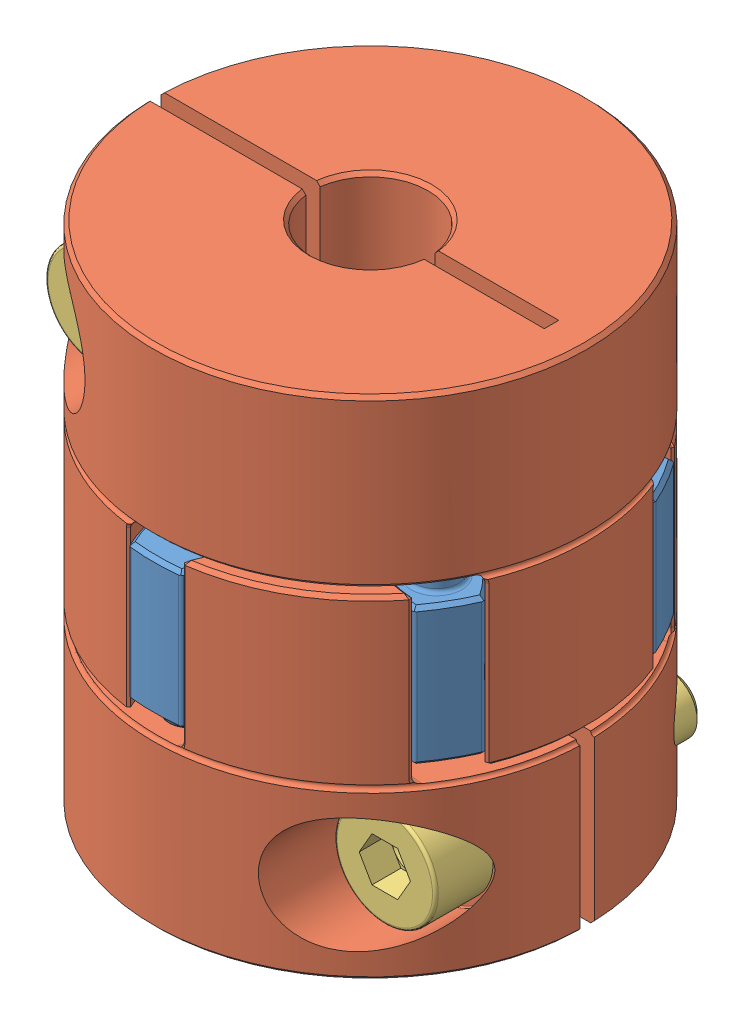
SolidWorks assembly Coupler D30L35-6.35-10.0, configuration Default. Lengths in mm.
Overall size (30.01 35 30).
5 component instances, 3 part files, 12 mates.
Components (placement in the parent):
- Coupler Spider-1: Coupler Spider [D30L35] at origin size (27.51 11.5 30)
- Coupler Jaw-3: Coupler Jaw [D30L35-10] at (0 -17.5 0) size (30.01 23 30)
- Coupler Jaw-4: Coupler Jaw [D30L35-8] at (0 17.5 0) x (-1 0 0) z (0 0 1) size (30.01 23 30)
- socket head cap screw_iso-1: socket head cap screw_iso [ISO 4762 M4 x 16 - 16N] at (10 -11.75 9) x (0 0 -1) z (0 1 0) size (20 7 7)
- socket head cap screw_iso-2: socket head cap screw_iso [ISO 4762 M4 x 16 - 16N] at (-10 11.75 9) x (0 0 -1) z (0 1 0) size (20 7 7)
Mates (geometry in assembly coordinates):
- Concentric3: concentric aligned: cylinder of Coupler Spider-1 through (0 4.75 0) axis (0 -1 0) radius 9; cylinder of Coupler Jaw-3 through (0 30.9558 0) axis (0 -1 0) radius 9
- Tangent3: tangent: cylinder of assembly; cylinder of assembly; cylinder of Coupler Spider-1 through (12.5 4.75 0) axis (0 -1 0) radius 9; cylinder of Coupler Jaw-3 through (12.5 30.9558 0) axis (0 -1 0) radius 9
- Concentric4: concentric: cylinder of assembly; cylinder of assembly; cylinder of Coupler Spider-1 through (0 4.75 0) axis (0 -1 0) radius 9; cylinder of Coupler Jaw-4 through (0 -30.9558 0) axis (0 1 0) radius 9
- Tangent4: tangent aligned: cylinder of Coupler Spider-1 through (6.25 4.75 10.8253) axis (0 -1 0) radius 9; cylinder of Coupler Jaw-4 through (6.25 -30.9558 10.8253) axis (0 1 0) radius 9
- Distance1: distance = 0.25 mm anti-aligned: plane of Coupler Spider-1 through (10.8253 5.75 6.25) normal (0 1 0); plane of Coupler Jaw-4 through (0 6 0) normal (0 -1 0)
- Distance2: distance = 0.25 mm: plane of assembly; plane of assembly; plane of Coupler Spider-1 through (10.8253 -5.75 -6.25) normal (0 -1 0); plane of Coupler Jaw-3 through (0 -6 0) normal (0 1 0)
- Concentric5: concentric anti-aligned: cone of Coupler Jaw-3 through (10 -11.75 5) axis (0 0 -1); cylinder of socket head cap screw_iso-1 through (10 -11.75 40.75) axis (0 0 1) radius 3.5
- Coincident1: coincident anti-aligned: plane of Coupler Jaw-3 through (12.5 -11.75 5) normal (0 0 1); plane of socket head cap screw_iso-1 through (6.5 -11.75 5) normal (0 0 -1)
- Concentric6: concentric anti-aligned: cone of Coupler Jaw-4 through (-10 11.75 5) axis (0 0 -1); cylinder of socket head cap screw_iso-2 through (-10 11.75 40.75) axis (0 0 1) radius 3.5
- Coincident2: coincident anti-aligned: plane of Coupler Jaw-4 through (-12.5 11.75 5) normal (0 0 1); plane of socket head cap screw_iso-2 through (-13.5 11.75 5) normal (0 0 -1)
- Parallel1: parallel aligned: plane of Coupler Spider-1 through (0 0 0) normal (0 1 0); plane of socket head cap screw_iso-1 through (10 -11.75 9) normal (0 1 0)
- Parallel2: parallel aligned: plane of Coupler Spider-1 through (0 0 0) normal (0 1 0); plane of socket head cap screw_iso-2 through (-10 11.75 9) normal (0 1 0)
